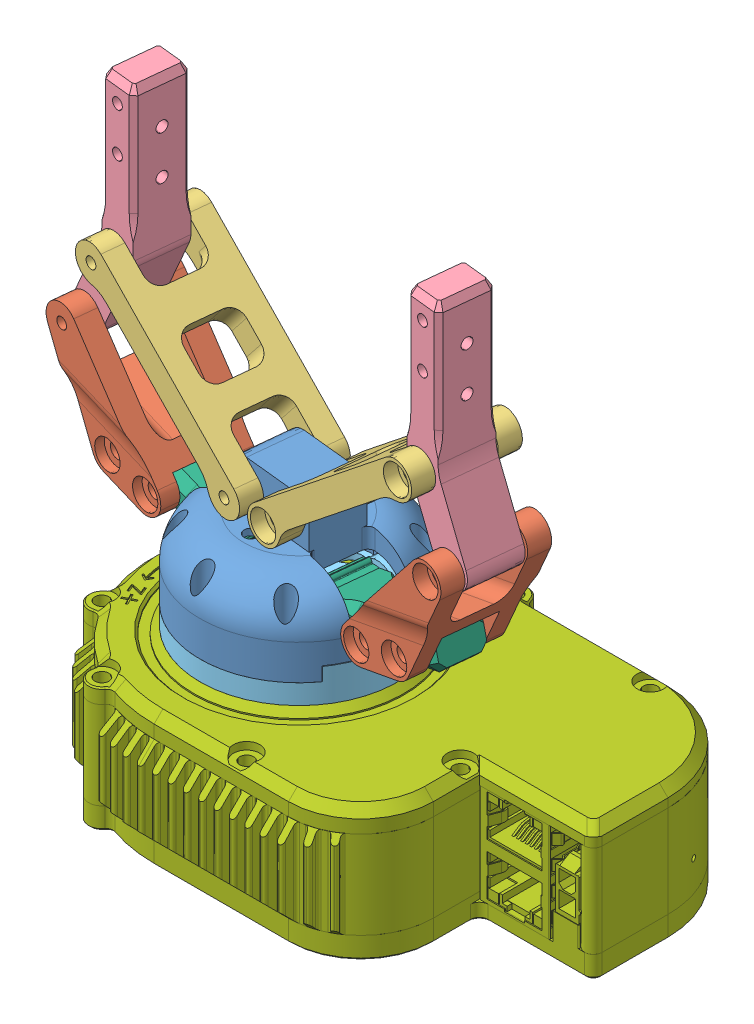
SolidWorks assembly Hebi Motor with Gripper, configuration Default. Lengths in mm.
Overall size (130.07 120.26 73.14).
12 component instances, 7 part files, 11 mates.
Components (placement in the parent):
- HEBI Robotics-A-2143-02-1: HEBI Robotics-A-2143-02 [Default] at (0 4.6253 0) x (0.994658 0 0.103227) z (-0.103227 0 0.994658) size (112.08 105.21 45) (flexible)
  - HEBI Robotics-A-2143-02_PM-2357-02-1: HEBI Robotics-A-2143-02_PM-2357-02 [Default] at (0 30.9247 0) x (0 0 -1) z (1 0 0) size (45 28 44.67)
  - HEBI Robotics-A-2143-02_PM-2358-02-1: HEBI Robotics-A-2143-02_PM-2358-02 [Default] at (-31.436 29.5333 0) x (0 0 -1) z (0.966127 -0.258068 0) size (23 26 33)
  - HEBI Robotics-A-2143-02_PM-2358-02-2: HEBI Robotics-A-2143-02_PM-2358-02 [Default] at (31.4354 29.5354 0) x (0 0 1) z (-0.966125 -0.258076 0) size (23 26 33)
  - HEBI Robotics-A-2143-02_PM-2359-02-1: HEBI Robotics-A-2143-02_PM-2359-02 [Default] at (21.9996 52.7813 0) x (0 0 1) z (0.775123 0.631811 0) size (23 8 51.86)
  - HEBI Robotics-A-2143-02_PM-2359-02-2: HEBI Robotics-A-2143-02_PM-2359-02 [Default] at (-22.0004 52.7803 0) x (0 0 -1) z (-0.775159 0.631767 0) size (23 8 51.86)
  - HEBI Robotics-A-2143-02_PM-2360-02-1: HEBI Robotics-A-2143-02_PM-2360-02 [Default] at (-39.0008 66.6359 0) x (-1 -0.000025 0) z (0 0 -1) size (15.5 54 12.08)
  - HEBI Robotics-A-2143-02_PM-2360-02-2: HEBI Robotics-A-2143-02_PM-2360-02 [Default] at (38.9992 66.6378 0) x (1 0.000025 0) z (0 0 1) size (15.5 54 12.08)
  - HEBI Robotics-A-2055-01_PM-2218-01-1: HEBI Robotics-A-2055-01_PM-2218-01 [Default] at (0 11.4247 0) size (45 32.5 45)
  - HEBI Robotics-A-2055-01_PM-2221-01-1: HEBI Robotics-A-2055-01_PM-2221-01 [Default] at (12.5 22.9247 0) x (0.966125 0.258076 0) z (0 0 1) size (35.49 9.86 12)
  - HEBI Robotics-A-2055-01_PM-2221-01-2: HEBI Robotics-A-2055-01_PM-2221-01 [Default] at (-12.5 22.9247 0) x (-0.966162 0.257934 0) z (0 0 -1) size (35.49 9.86 12)
- HEBI Robotics-X5-Export-2021-1: HEBI Robotics-X5-Export-2021 [Default] x (1 0 0) z (0 1 0) size (109.71 73.14 31.05)
Mates (geometry in assembly coordinates):
- Coincident6: coincident: point of HEBI Robotics-X5-Export-2021-1
- Coincident8: coincident anti-aligned: plane of HEBI Robotics-A-2143-02-1/HEBI Robotics-A-2055-01_PM-2218-01-1 through (0 16.05 0) normal (0 -1 0); plane of HEBI Robotics-X5-Export-2021-1 through (0 16.05 0) normal (0 1 0)
- Concentric1: concentric anti-aligned: cylinder of HEBI Robotics-A-2143-02-1/HEBI Robotics-A-2055-01_PM-2218-01-1 through (0 22.55 0) axis (0 -1 0) radius 22.5; circle of HEBI Robotics-X5-Export-2021-1
- Coincident10: coincident aligned: plane of HEBI Robotics-X5-Export-2021-1 through (0 0 0) normal (0 1 0)
- Coincident11: coincident anti-aligned: plane of HEBI Robotics-X5-Export-2021-1 through (0 0 0) normal (0 0 -1)
- Width1: width aligned: plane of gripper finger-1 through (-11.0846 140.8097 18.957) normal (-0.103227 0 0.994658); plane of gripper finger-1 through (-6.9555 140.8097 -20.8293) normal (0.103227 0 -0.994658); plane of HEBI Robotics-A-2143-02-1/HEBI Robotics-A-2143-02_PM-2360-02-2 through (45.6318 55.2633 10.768) normal (-0.103227 0 0.994658); plane of HEBI Robotics-A-2143-02-1/HEBI Robotics-A-2143-02_PM-2360-02-2 through (46.8706 55.2633 -1.1679) normal (0.103227 0 -0.994658)
- Coincident14: coincident aligned: plane of Checker_40mm-1 through (0 210.7174 0) normal (0 0 1)
- Coincident15: coincident aligned: plane of Checker_40mm-1 through (0 210.7174 0) normal (1 0 0)
- Concentric2: concentric aligned: cylinder of HEBI Robotics-A-2143-02-1/HEBI Robotics-A-2143-02_PM-2360-02-1 through (-39.4125 100.2612 1.9419) axis (-0.103227 0 0.994658) radius 1.25; cylinder of gripper finger-1 through (-33.0022 104.3091 -23.5324) axis (-0.103227 0 0.994658) radius 1.75
- Concentric3: concentric aligned: cylinder of HEBI Robotics-A-2143-02-1/HEBI Robotics-A-2143-02_PM-2360-02-1 through (-39.4123 90.2612 1.942) axis (-0.103227 0 0.994658) radius 1.25; cylinder of gripper finger-1 through (-33.0019 94.3091 -23.5324) axis (-0.103227 0 0.994658) radius 1.75
- Width5: width anti-aligned: plane of gripper finger-1 through (-10.6717 140.8097 14.9784) normal (-0.103227 0 0.994658); plane of gripper finger-1 through (-7.3684 140.8097 -16.8506) normal (0.103227 0 -0.994658); plane of HEBI Robotics-A-2143-02-1/HEBI Robotics-A-2143-02_PM-2360-02-1 through (-45.6326 55.261 -10.768) normal (0.103227 0 -0.994658); plane of HEBI Robotics-A-2143-02-1/HEBI Robotics-A-2143-02_PM-2360-02-1 through (-46.8713 55.261 1.1679) normal (-0.103227 0 0.994658)
